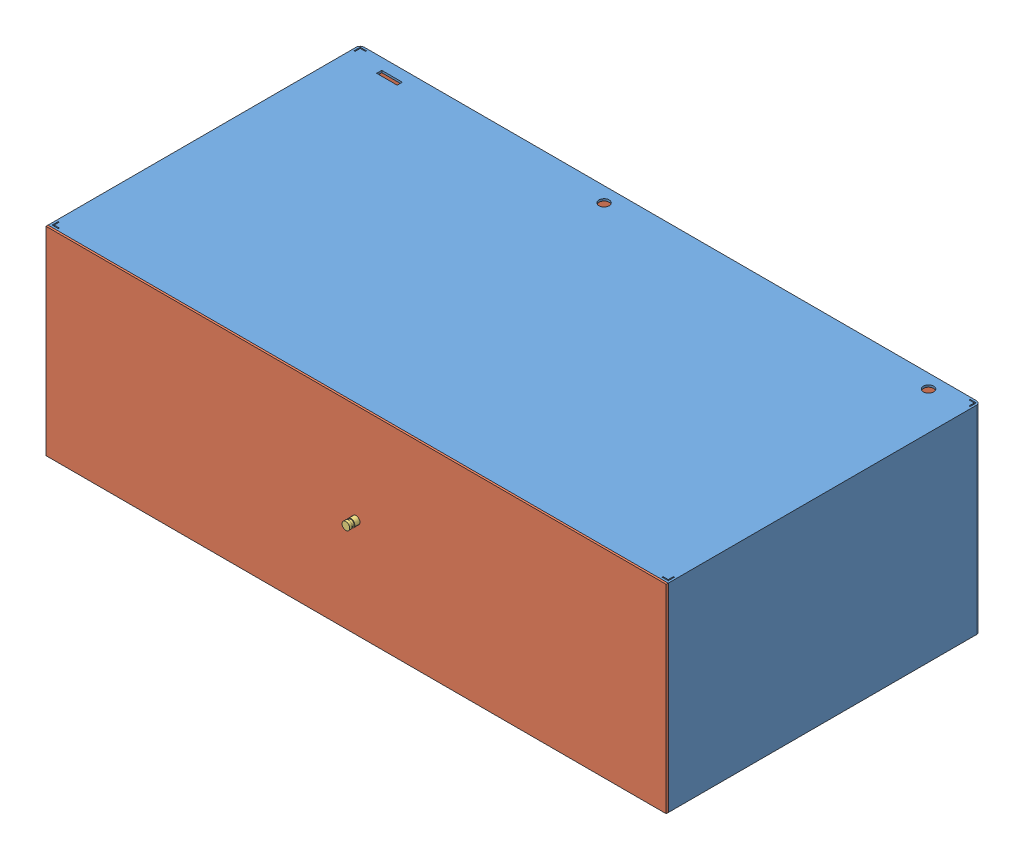
SolidWorks assembly A_Reservatorio, configuration Default. Lengths in mm.
Overall size (1208 407 632).
7 component instances, 4 part files, 5 mates.
Components (placement in the parent):
- EstruturaReservatorio-1: EstruturaReservatorio [Default] at (444.341 733.9299 556.3755) size (1208 387 608)
- PortaReservatorio-1: PortaReservatorio [Default] at (444.341 733.9299 1164.3763) size (1208 387 608)
- PuxadorGavetaReservatorio-1: PuxadorGavetaReservatorio [Default] at (444.341 733.9299 1188.3763) x (0.021258 -0.999774 0) z (0 0 1) size (15 15 20)
- ApoioReservatorio-1: ApoioReservatorio [Default] at (948.341 520.4299 1084.3755) x (0.91987 0 -0.392224) z (0.392224 0 0.91987) size (50 20 50)
- ApoioReservatorio-2: ApoioReservatorio [Default] at (-59.659 520.4299 1084.3755) x (0.91987 0 -0.392224) z (0.392224 0 0.91987) size (50 20 50)
- ApoioReservatorio-3: ApoioReservatorio [Default] at (948.341 520.4299 636.3755) x (0.91987 0 -0.392224) z (0.392224 0 0.91987) size (50 20 50)
- ApoioReservatorio-4: ApoioReservatorio [Default] at (-59.659 520.4299 636.3755) x (0.91987 0 -0.392224) z (0.392224 0 0.91987) size (50 20 50)
Mates (geometry in assembly coordinates):
- Coincident11: coincident: circle of PortaReservatorio-1; circle of PuxadorGavetaReservatorio-1
- Coincident12: coincident: circle of EstruturaReservatorio-1; circle of ApoioReservatorio-1
- Perpendicular1: perpendicular: line of EstruturaReservatorio-1 through (-155.659 923.4299 1164.3755) axis (1 0 0); line of PortaReservatorio-1 through (1044.341 921.4299 560.3763) axis (0 -1 0)
- Distance1: distance = 2 mm: plane of PortaReservatorio-1 through (444.341 546.4299 1164.3763) normal (0 -1 0); plane of EstruturaReservatorio-1 through (-155.659 544.4299 560.3755) normal (0 1 0)
- Coincident15: coincident: plane of PortaReservatorio-1 through (1044.341 921.4299 1164.3763) normal (1 0 0); plane of EstruturaReservatorio-1 through (1044.341 923.4299 560.3755) normal (-1 0 0)
